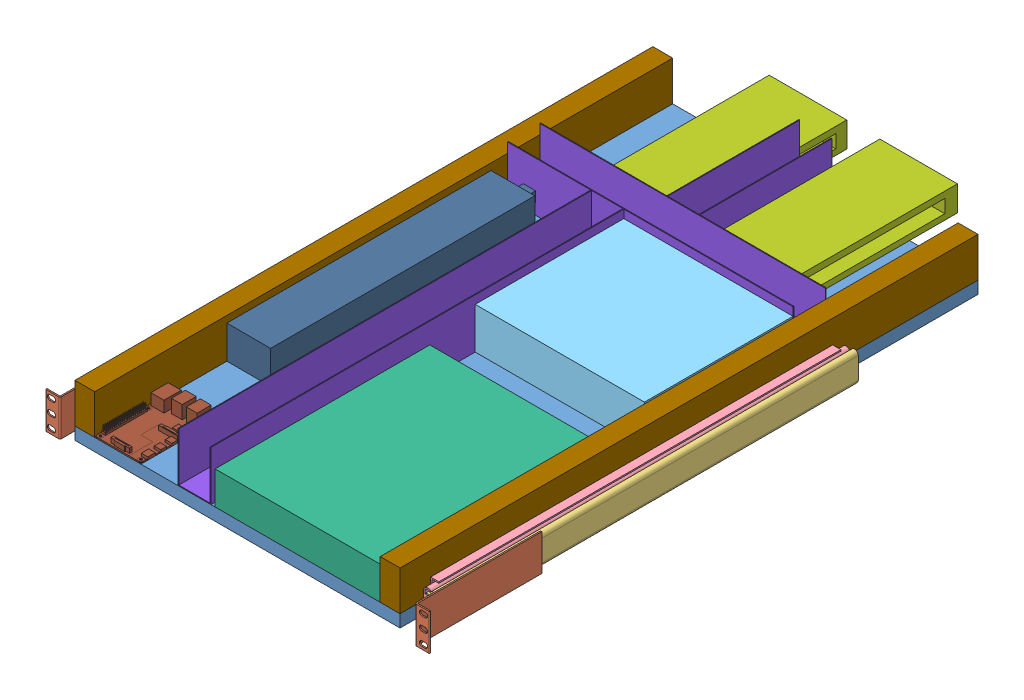
SolidWorks assembly Router-Schublade, configuration Standard. Lengths in mm.
Overall size (464.8 84.05 758.02).
20 component instances, 11 part files, 39 mates.
Components (placement in the parent):
- Platte-1: Platte [Standard] at (-201.5811 50.5043 900) size (393.8 15 700)
- Gleitschiene-Left-1: Gleitschiene-Left [Standard] at (-230.5216 -87.7457 847.2457) x (0 0 1) z (0 1 0) size (537 44.1 44)
  - winkel-1: winkel [Standard] at (51.9543 -6.5595 130.1) size (152.1 17.5 44)
  - Schine-1: Schine [Standard] at (-484.2457 10.9405 134.15) x (0 1 0) z (1 0 0) size (13.6 35 510)
  - Rolle-1: Rolle [Standard] at (-471.2457 35.9405 133.25) x (0 1 0) z (1 0 0) size (19.2 41.6 507)
- Gleitschiene-Right-1: Gleitschiene-Right [Standard] at (221.1594 215.5543 847.2457) x (0 0 1) z (0 -1 0) size (537 44.1 44.05)
  - winkel-1: winkel [Standard] at (51.9543 -6.5595 130.1) size (152.1 17.5 44)
  - Schine-1: Schine [Standard] at (-484.2457 10.9405 134.15) x (0 1 0) z (1 0 0) size (13.6 35 510)
  - Rolle-1: Rolle [Standard] at (15.7543 35.9405 170.05) x (0 1 0) z (-1 0 0) size (19.2 41.6 507)
- Modem-1: Modem [Standard] at (168.2189 115.5043 580) x (-1 0 0) z (0 -1 0) size (205 180 50)
- Router-1: Router [Standard] at (168.2189 65.5043 900) x (0 0 -1) z (1 0 0) size (260 40 200)
- Keystone Housing-1: Keystone Housing [Standard] at (-24.6811 65.5043 360) x (0 0 -1) z (1 0 0) size (218 30.5 94)
- Keystone Housing-2: Keystone Housing [Standard] at (15.3189 65.5043 142) x (0 0 1) z (-1 0 0) size (218 30.5 94)
- Kanal-1: Kanal [500] at (-56.7811 65.5043 400) size (40 60 500)
- Kanal-2: Kanal [160] at (-4.6811 65.5043 200) size (40 60 160)
- Seite-1: Seite [Standard] at (-201.5811 65.5043 200) size (24 48 700)
- Seite-2: Seite [Standard] at (168.2189 65.5043 200) size (24 48 700)
- Steckdose-1: Steckdose [Standard] at (-177.5811 65.5043 740) size (53 40 340)
- Kanal-3: Kanal [345,8] at (168.2189 65.5043 380) x (0 0 1) z (-1 0 0) size (40 60 345.8)
- Raspberry Pi 4 B-1: Raspberry Pi 4 B [默认] at (-135.4811 64.1043 852.8) x (0 0 -1) z (0 1 0) size (86.92 58.6 19)
Mates (geometry in assembly coordinates):
- Deckungsgleich1: coincident anti-aligned: plane of Platte-1 through (-201.5811 65.5043 900) normal (-1 0 0); plane of Gleitschiene-Left-1/Rolle-1 through (-201.5811 45.5043 863) normal (1 0 0)
- Deckungsgleich2: coincident anti-aligned: plane of Platte-1 through (-201.5811 50.5043 900) normal (0 -1 0); plane of Gleitschiene-Left-1/Rolle-1 through (-192.9811 50.5043 863) normal (0 1 0)
- Abstand1: distance = 37 mm aligned: plane of Platte-1 through (-201.5811 65.5043 900) normal (0 0 1); plane of Gleitschiene-Left-1/Rolle-1 through (-194.5811 45.5043 863) normal (0 0 1)
- Deckungsgleich4: coincident anti-aligned: plane of Platte-1 through (192.2189 65.5043 900) normal (1 0 0); plane of Gleitschiene-Right-1/Rolle-1 through (192.2189 45.5043 376) normal (-1 0 0)
- Deckungsgleich5: coincident anti-aligned: plane of Platte-1 through (-201.5811 50.5043 900) normal (0 -1 0); plane of Gleitschiene-Right-1/Rolle-1 through (183.6189 50.5043 376) normal (0 1 0)
- Abstand2: distance = 37 mm aligned: plane of Platte-1 through (-201.5811 65.5043 900) normal (0 0 1); plane of Gleitschiene-Right-1/Rolle-1 through (185.2189 45.5043 863) normal (0 0 1)
- Deckungsgleich7: coincident anti-aligned: plane of Platte-1 through (-201.5811 65.5043 900) normal (0 1 0); plane of Modem-1 through (168.2189 65.5043 580) normal (0 -1 0)
- Deckungsgleich8: coincident anti-aligned: plane of Platte-1 through (-201.5811 65.5043 900) normal (0 1 0); plane of Router-1 through (168.2189 65.5043 900) normal (0 -1 0)
- Deckungsgleich11: coincident anti-aligned: plane of Platte-1 through (-201.5811 65.5043 900) normal (0 1 0); plane of Keystone Housing-2 through (15.3189 65.5043 142) normal (0 -1 0)
- Deckungsgleich15: coincident anti-aligned: plane of Platte-1 through (-201.5811 65.5043 900) normal (0 1 0); plane of Keystone Housing-1 through (-24.6811 65.5043 360) normal (0 -1 0)
- Deckungsgleich16: coincident anti-aligned: plane of Platte-1 through (-201.5811 65.5043 900) normal (0 1 0); plane of Kanal-1 through (-36.7811 65.5043 900) normal (0 -1 0)
- Deckungsgleich17: coincident aligned: plane of Platte-1 through (-201.5811 65.5043 900) normal (0 0 1); plane of Kanal-1 through (-56.7811 65.5043 900) normal (0 0 1)
- Deckungsgleich18: coincident anti-aligned: plane of Platte-1 through (-201.5811 65.5043 900) normal (0 1 0); plane of Kanal-2 through (15.3189 65.5043 360) normal (0 -1 0)
- Deckungsgleich19: coincident aligned: plane of Platte-1 through (-201.5811 65.5043 200) normal (0 0 -1); plane of Kanal-2 through (-4.6811 65.5043 200) normal (0 0 -1)
- Deckungsgleich20: coincident anti-aligned: plane of Platte-1 through (-201.5811 65.5043 900) normal (0 1 0); plane of Seite-1 through (-201.5811 65.5043 900) normal (0 -1 0)
- Deckungsgleich21: coincident anti-aligned: plane of Platte-1 through (-201.5811 65.5043 900) normal (0 1 0); plane of Seite-2 through (168.2189 65.5043 900) normal (0 -1 0)
- Deckungsgleich22: coincident aligned: plane of Platte-1 through (-201.5811 65.5043 900) normal (0 0 1); plane of Seite-2 through (168.2189 65.5043 900) normal (0 0 1)
- Deckungsgleich23: coincident aligned: plane of Platte-1 through (-201.5811 65.5043 900) normal (0 0 1); plane of Seite-1 through (-201.5811 65.5043 900) normal (0 0 1)
- Deckungsgleich24: coincident anti-aligned: plane of Gleitschiene-Left-1/Rolle-1 through (-201.5811 45.5043 863) normal (1 0 0); plane of Seite-1 through (-201.5811 65.5043 900) normal (-1 0 0)
- Deckungsgleich25: coincident anti-aligned: plane of Gleitschiene-Right-1/Rolle-1 through (192.2189 45.5043 376) normal (-1 0 0); plane of Seite-2 through (192.2189 65.5043 900) normal (1 0 0)
- Deckungsgleich27: coincident anti-aligned: plane of Router-1 through (168.2189 105.5043 900) normal (1 0 0); plane of Seite-2 through (168.2189 65.5043 900) normal (-1 0 0)
- Deckungsgleich28: coincident aligned: plane of Platte-1 through (-201.5811 65.5043 900) normal (0 0 1); plane of Router-1 through (168.2189 105.5043 900) normal (0 0 1)
- Deckungsgleich31: coincident anti-aligned: plane of Modem-1 through (168.2189 65.5043 580) normal (1 0 0); plane of Seite-2 through (168.2189 65.5043 900) normal (-1 0 0)
- Deckungsgleich32: coincident anti-aligned: plane of Platte-1 through (-201.5811 65.5043 900) normal (0 1 0); plane of Steckdose-1 through (-177.5811 65.5043 740) normal (0 -1 0)
- Deckungsgleich33: coincident anti-aligned: plane of Seite-1 through (-177.5811 65.5043 900) normal (1 0 0); plane of Steckdose-1 through (-177.5811 105.5043 740) normal (-1 0 0)
- Deckungsgleich34: coincident anti-aligned: plane of Platte-1 through (-201.5811 65.5043 900) normal (0 1 0); plane of Kanal-3 through (-177.5811 65.5043 400) normal (0 -1 0)
- Deckungsgleich35: coincident anti-aligned: plane of Seite-2 through (168.2189 65.5043 900) normal (-1 0 0); plane of Kanal-3 through (168.2189 65.5043 380) normal (1 0 0)
- Deckungsgleich38: coincident anti-aligned: plane of Kanal-1 through (-56.7811 65.5043 400) normal (0 0 -1); plane of Kanal-3 through (-177.5811 125.5043 400) normal (0 0 1)
- Deckungsgleich39: coincident anti-aligned: plane of Modem-1 through (-36.7811 65.5043 580) normal (-1 0 0); plane of Kanal-1 through (-36.7811 125.5043 900) normal (1 0 0)
- Deckungsgleich40: coincident anti-aligned: plane of Modem-1 through (168.2189 65.5043 400) normal (0 0 -1); plane of Kanal-3 through (-177.5811 125.5043 400) normal (0 0 1)
- Deckungsgleich41: coincident anti-aligned: plane of Steckdose-1 through (-158.5811 105.5043 400) normal (0 0 -1); plane of Kanal-3 through (-177.5811 125.5043 400) normal (0 0 1)
- Deckungsgleich42: coincident anti-aligned: plane of Keystone Housing-1 through (-24.6811 96.0043 360) normal (0 0 1); plane of Kanal-3 through (-177.5811 65.5043 360) normal (0 0 -1)
- Deckungsgleich43: coincident anti-aligned: plane of Keystone Housing-2 through (15.3189 96.0043 360) normal (0 0 1); plane of Kanal-3 through (-177.5811 65.5043 360) normal (0 0 -1)
- Deckungsgleich44: coincident anti-aligned: plane of Keystone Housing-1 through (-24.6811 96.0043 360) normal (1 0 0); plane of Kanal-2 through (-24.6811 65.5043 360) normal (-1 0 0)
- Deckungsgleich45: coincident anti-aligned: plane of Keystone Housing-2 through (15.3189 96.0043 142) normal (-1 0 0); plane of Kanal-2 through (15.3189 125.5043 360) normal (1 0 0)
- Breite1: width aligned: plane of Seite-1 through (-177.5811 65.5043 900) normal (1 0 0); plane of Seite-2 through (168.2189 65.5043 900) normal (-1 0 0); plane of Keystone Housing-2 through (109.3189 96.0043 142) normal (1 0 0); plane of Keystone Housing-1 through (-118.6811 96.0043 360) normal (-1 0 0)
- Deckungsgleich46: coincident: plane of Platte-1 through (-201.5811 65.5043 900) normal (0 1 0); plane of Raspberry Pi 4 B-1 through (-151.8253 65.5043 855.7172) normal (0 1 0)
- Deckungsgleich47: coincident: plane of Seite-1 through (-201.5811 65.5043 900) normal (0 0 1); plane of Raspberry Pi 4 B-1 through (-149.5877 65.9048 900) normal (0 0 -1)
- Deckungsgleich49: coincident aligned: plane of Seite-1 through (-177.5811 65.5043 900) normal (1 0 0); plane of Raspberry Pi 4 B-1 through (-177.5811 65.9049 839.2776) normal (1 0 0)
